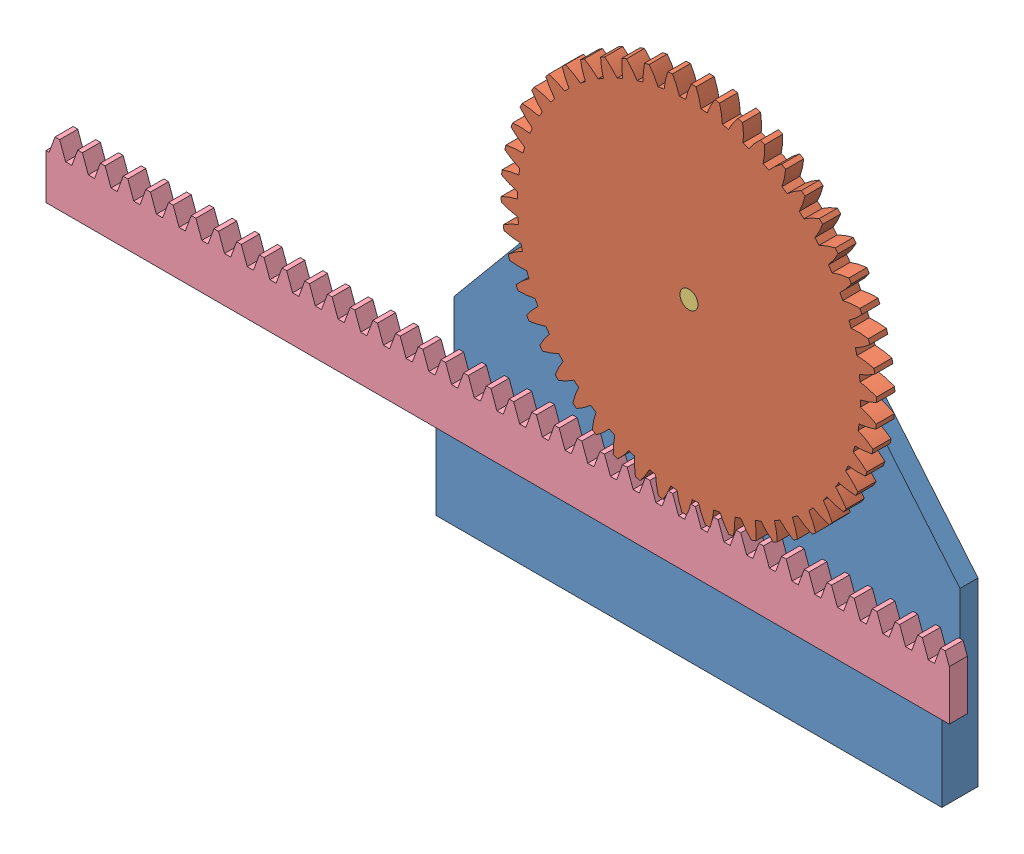
SolidWorks assembly HW8_WONG_P3, configuration Default. Lengths in mm.
Overall size (250 162.72 10).
4 component instances, 4 part files, 9 mates.
Components (placement in the parent):
- rp_base-1: rp_base [Default] at origin size (140 110 10)
- rp_gear-1: rp_gear [Metric - Spur gear 2M 50T 20PA 5FW ---S50N75H50L5N] at (-79.5647 27.3579 0) x (0 0 -1) z (-0.999298 -0.037473 0) size (5 158.93 104)
- rp_pin-1: rp_pin [Default] at origin size (20 16.61 10)
- rp_rack-1: rp_rack [Metric - Rack-spur - rectangular 2M 20PA 5FW 15PH 250L---SAll] at (-257.5147 -38.3958 0) size (250 17 5)
Mates (geometry in assembly coordinates):
- Coincident2: coincident anti-aligned: plane of rp_base-1 through (0 -38.3958 -10) normal (0 1 0); plane of rp_rack-1 through (-257.5147 -38.3958 -5) normal (0 -1 0)
- Coincident3: coincident anti-aligned: plane of rp_base-1 through (0 0 -5) normal (0 0 1); plane of rp_rack-1 through (-257.5147 -21.3958 -5) normal (0 0 -1)
- Concentric1: concentric anti-aligned: cylinder of rp_base-1 through (-79.5647 27.3579 -5) axis (0 0 -1) radius 10; cylinder of rp_pin-1 through (-79.5647 27.3579 -10) axis (0 0 1) radius 10
- Coincident4: coincident anti-aligned: plane of rp_base-1 through (0 20.7435 -5) normal (0 1 0); plane of rp_pin-1 through (0 20.7435 -10) normal (0 -1 0)
- Coincident5: coincident aligned: plane of rp_base-1 through (0 0 -5) normal (0 0 1); plane of rp_pin-1 through (0 0 -5) normal (0 0 1)
- Coincident6: coincident anti-aligned: plane of rp_base-1 through (0 0 -5) normal (0 0 1); plane of rp_gear-1 through (-79.5647 27.3579 -5) normal (0 0 -1)
- Concentric2: concentric aligned: cylinder of rp_gear-1 through (-79.5647 27.3579 -50.0001) axis (0 0 1) radius 2.5; cylinder of rp_pin-1 through (-79.5647 27.3579 -10) axis (0 0 1) radius 2.5
- RackPinionMate7: rack pinion = 100 mm: line of rp_rack-1 through (250 -257.5147 -38.3958) axis (0 1 0); circle of rp_gear-1
- LimitDistance1: limit distance = 107.95 mm aligned: plane of rp_rack-1 through (-257.5147 -38.3958 -5) normal (-1 0 0); plane of rp_base-1 through (-149.5647 0 -5) normal (-1 0 0)
